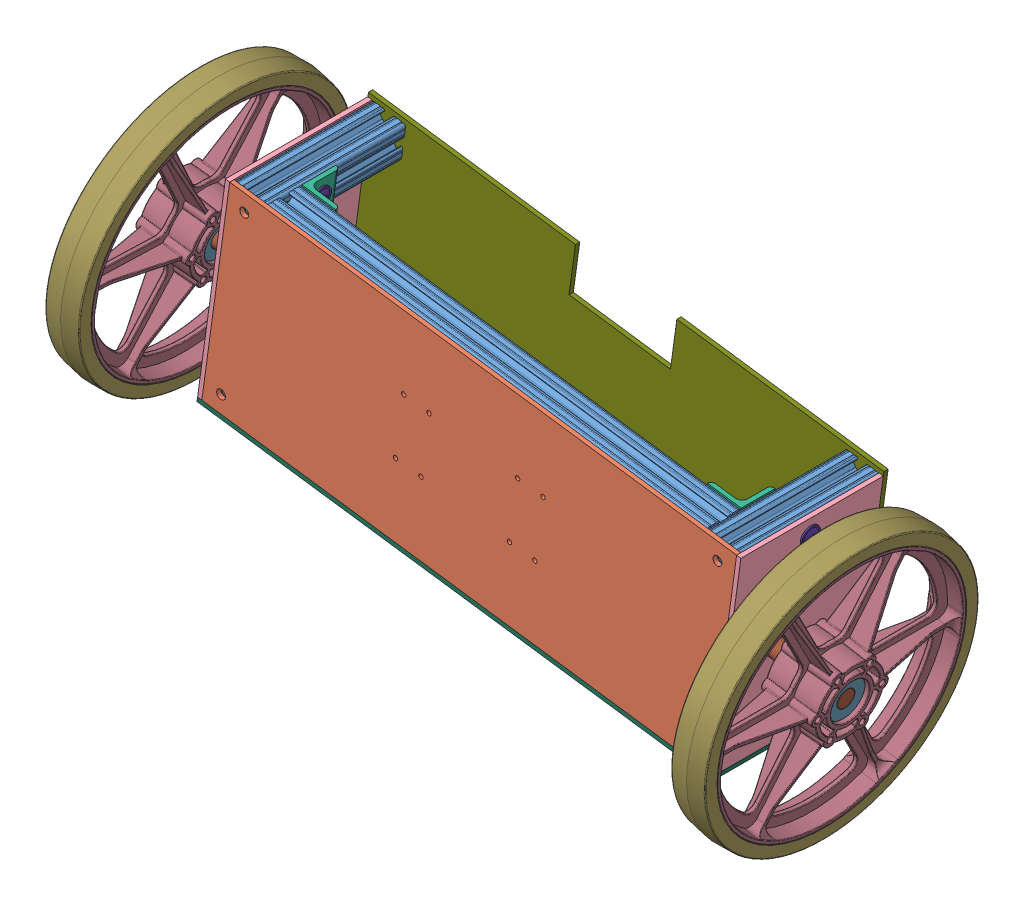
SolidWorks assembly MotorBox_Assy, configuration Default. Lengths in mm.
Overall size (541.44 344.28 279.2).
49 component instances, 18 part files, 75 mates.
Components (placement in the parent):
- 1010 PROFILE-3: 1010 PROFILE [13] at (161.8359 -35.0491 -15.875) x (-0.136082 -0.990698 0) z (0.990698 -0.136082 0) size (25.4 25.4 330.2)
- MotorBox_Base-1: MotorBox_Base [Default] at (-10.3695 -75.4912 -3.175) x (-0.990698 0.136082 0) z (0.136082 0.990698 0) size (381 3.17 152.4)
- Motor_Bracket-2: Motor_Bracket [Default] at (-159.2475 -55.0412 -31.75) x (0.136082 0.990698 0) z (-0.990698 0.136082 0) size (88.9 50.8 20.96)
- Motor_Bracket-3: Motor_Bracket [Default] at (138.5085 -95.9411 -31.75) x (-0.136082 -0.990698 0) z (0.990698 -0.136082 0) size (88.9 50.8 20.96)
- MotorBox_BackPlate-1: MotorBox_BackPlate [Default] at (0 0 -53.0225) x (0.990698 -0.136082 0) z (0.136082 0.990698 0) size (387.35 106.05 3.17) (hidden)
- 1010 PROFILE-5: 1010 PROFILE [4.05] at (-177.8743 11.6136 -3.175) x (0.990698 -0.136082 0) z (0 0 1) size (25.4 25.4 102.87)
- 1010 PROFILE-6: 1010 PROFILE [4.05] at (174.4178 -36.7773 -3.175) x (0.990698 -0.136082 0) z (0 0 1) size (25.4 25.4 102.87)
- motorbox_sidePlate-1: motorbox_sidePlate [Default] at (188.7279 -25.9237 0) x (0.990698 -0.136082 0) z (0.136082 0.990698 0) size (3.17 106.05 152.4)
- motorbox_sidePlate-3: motorbox_sidePlate [Default] at (-191.8733 26.3558 0) x (0.990698 -0.136082 0) z (0.136082 0.990698 0) size (3.17 106.05 152.4)
- MotorMount_3Dp2-1: MotorMount_3Dp2 [Default] at (17.0936 -79.2635 -3.175) x (-0.136082 -0.990698 0) z (0.990698 -0.136082 0) size (57.15 50.9 30.48)
- MotorMount_3Dp2-2: MotorMount_3Dp2 [Default] at (-37.8325 -71.7188 -3.175) x (0.136082 0.990698 0) z (-0.990698 0.136082 0) size (57.15 50.9 30.48)
- 90Deg 2Hole 4108-5: 90Deg 2Hole 4108 [Default] at (-190.2753 0.4978 -55.6714) x (0.990698 -0.136082 0) z (0.136082 0.990698 0) size (25.4 25.4 25.4)
- 90Deg 2Hole 4108-6: 90Deg 2Hole 4108 [Default] at (186.8188 -25.6615 -55.6714) x (-0.990698 0.136082 0) z (-0.136082 -0.990698 0) size (25.4 25.4 25.4)
- Motor_Coupler_WheelAssy-1: Motor_Coupler_WheelAssy [Default] at (82.653 -91.6609 -43.1023) x (0.117796 0.857568 -0.500701) z (-0.990698 0.136082 0) size (204.35 204.35 248.71)
  - Motor-1: Motor [Default] at (-2.7115 -11.3995 12.6743) size (45.1 45.1 159.4)
  - Coupler_Assembly-1: Coupler_Assembly [Default] at (-18.5282 -16.0979 -94.9854) x (0.697262 -0.716816 0) z (0 0 1) size (25.52 25.52 28.68)
    - CouplingCenter_59985K630-1: CouplingCenter_59985K630 [59985K63] at (7.6605 14.6137 19.5344) size (25.4 25.4 7.92)
    - halfInCoupling_59985K190-1: halfInCoupling_59985K190 [59985K19] at (7.6605 14.6137 19.4804) size (25.52 25.52 14.06)
    - 10mmCoupling_59985K305-1: 10mmCoupling_59985K305 [59985K305] at (7.6605 14.6137 19.5884) x (0 1 0) z (0 0 -1) size (25.52 25.52 14.06)
  - HalfInch_Shaft-1: HalfInch_Shaft [Default] at (-2.7115 -11.3995 -156.5786) size (12.7 12.7 76.2)
  - 8inWheel_AndyMarkAlternative-1: 8inWheel_AndyMarkAlternative [Default] at (-2.7115 -11.3995 -153.4798) size (204.35 204.35 38.11)
    - 2010 8 tread-1: 2010 8 tread [Default] at (0 0 12.7) size (204.35 204.35 25.4)
    - 2010 8 hub-1: 2010 8 hub [Default] at origin size (190.5 190.5 38.11)
    - r8 bearing-1: r8 bearing [Default] at (0 0 -3.0988) x (-0.726935 0.686706 0) z (0 0 1) size (28.57 28.57 6.35)
    - r8 bearing-2: r8 bearing [Default] at (0 0 28.575) x (0.399336 0.916804 0) z (0 0 -1) size (28.57 28.57 6.35)
- Motor_Coupler_WheelAssy-2: Motor_Coupler_WheelAssy [Default] at (-104.2482 -65.5549 -20.405) x (0.120301 0.875807 0.467429) z (0.990698 -0.136082 0) size (204.35 204.35 248.71)
  - Motor-1: Motor [Default] at (-2.7115 -11.3995 12.6743) size (45.1 45.1 159.4)
  - Coupler_Assembly-1: Coupler_Assembly [Default] at (-18.5282 -16.0979 -94.9854) x (0.697262 -0.716816 0) z (0 0 1) size (25.52 25.52 28.68)
    - CouplingCenter_59985K630-1: CouplingCenter_59985K630 [59985K63] at (7.6605 14.6137 19.5344) size (25.4 25.4 7.92)
    - halfInCoupling_59985K190-1: halfInCoupling_59985K190 [59985K19] at (7.6605 14.6137 19.4804) size (25.52 25.52 14.06)
    - 10mmCoupling_59985K305-1: 10mmCoupling_59985K305 [59985K305] at (7.6605 14.6137 19.5884) x (0 1 0) z (0 0 -1) size (25.52 25.52 14.06)
  - HalfInch_Shaft-1: HalfInch_Shaft [Default] at (-2.7115 -11.3995 -156.5786) size (12.7 12.7 76.2)
  - 8inWheel_AndyMarkAlternative-1: 8inWheel_AndyMarkAlternative [Default] at (-2.7115 -11.3995 -153.4798) size (204.35 204.35 38.11)
    - 2010 8 tread-1: 2010 8 tread [Default] at (0 0 12.7) size (204.35 204.35 25.4)
    - 2010 8 hub-1: 2010 8 hub [Default] at origin size (190.5 190.5 38.11)
    - r8 bearing-1: r8 bearing [Default] at (0 0 -3.0988) x (-0.726935 0.686706 0) z (0 0 1) size (28.57 28.57 6.35)
    - r8 bearing-2: r8 bearing [Default] at (0 0 28.575) x (0.399336 0.916804 0) z (0 0 -1) size (28.57 28.57 6.35)
- 1010 PROFILE-7: 1010 PROFILE [4.05] at (157.1353 -162.5959 -3.175) x (-0.136082 -0.990698 0) z (0 0 1) size (25.4 25.4 102.87)
- 1010 PROFILE-8: 1010 PROFILE [4.05] at (-195.1567 -114.205 -3.175) x (-0.136082 -0.990698 0) z (0 0 1) size (25.4 25.4 102.87)
- MotorBox_FrontPlate-1: MotorBox_FrontPlate [Default] at (-21.171 -154.1278 -53.0225) x (0.990698 -0.136082 0) z (0.136082 0.990698 0) size (387.35 106.05 3.17)
- MotorBox_TopPlate-1: MotorBox_TopPlate [Default] at (-10.3695 -75.4912 -109.22) x (-0.990698 0.136082 0) z (0 0 1) size (387.35 158.75 3.17)
- Tnut_47065T142-1: Tnut_47065T142 [47065T142] at (177.5632 -37.2094 -52.959) x (-0.136082 -0.990698 0) z (0 0 1) size (13.84 15.48 25.4)
- Tnut_47065T142-2: Tnut_47065T142 [47065T142] at (160.2808 -163.028 -52.959) x (-0.136082 -0.990698 0) z (0 0 1) size (13.84 15.48 25.4)
- Tnut_47065T142-3: Tnut_47065T142 [47065T142] at (-181.0197 12.0457 -52.959) x (0.136082 0.990698 0) z (0 0 1) size (13.84 15.48 25.4)
- Tnut_47065T142-4: Tnut_47065T142 [47065T142] at (-198.3022 -113.7729 -52.959) x (0.136082 0.990698 0) z (0 0 1) size (13.84 15.48 25.4)
- Tnut_47065T142-5: Tnut_47065T142 [47065T142] at (-152.7105 8.1571 -19.05) x (0.136082 0.990698 0) z (-0.990698 0.136082 0) size (13.84 15.48 25.4)
- Tnut_47065T142-6: Tnut_47065T142 [47065T142] at (-174.7288 11.1815 -41.275) x (-0.136082 -0.990698 0) z (0 0 1) size (13.84 15.48 25.4)
- Tnut_47065T142-7: Tnut_47065T142 [47065T142] at (171.2723 -36.3453 -41.275) x (-0.135988 -0.990011 0.037224) z (-0.005066 -0.036878 -0.999307) size (13.84 15.48 25.4)
- Tnut_47065T142-8: Tnut_47065T142 [47065T142] at (149.2541 -33.3208 -19.05) x (0.136082 0.990698 0) z (-0.990698 0.136082 0) size (13.84 15.48 25.4)
Mates (geometry in assembly coordinates):
- Coincident34: coincident anti-aligned: plane of MotorBox_Base-1 through (-10.3695 -75.4912 -3.175) normal (0 0 -1); plane of Motor_Bracket-2 through (-150.0531 -11.4368 -3.175) normal (0 0 1)
- Coincident39: coincident anti-aligned: plane of MotorBox_Base-1 through (-10.3695 -75.4912 -3.175) normal (0 0 -1); plane of Motor_Bracket-3 through (129.3142 -139.5455 -3.175) normal (0 0 1)
- Coincident44: coincident aligned: plane of MotorBox_Base-1 through (-10.3695 -75.4912 0) normal (0 0 1); plane of MotorBox_BackPlate-1 through (-191.4413 29.5012 0) normal (0 0 1)
- Distance23: distance = 3.175 mm aligned: plane of MotorBox_Base-1 through (-209.4668 -125.0586 0) normal (-0.990698 0.136082 0); plane of MotorBox_BackPlate-1 through (-191.4413 29.5012 -106.045) normal (-0.990698 0.136082 0)
- Coincident46: coincident anti-aligned: plane of MotorBox_Base-1 through (188.7279 -25.9237 0) normal (0.136082 0.990698 0); plane of MotorBox_BackPlate-1 through (0 0 -53.0225) normal (-0.136082 -0.990698 0)
- Distance18: distance = 12.7 mm anti-aligned: plane of 1010 PROFILE-3; plane of 1010 PROFILE-5 through (-177.8743 11.6136 -3.175) normal (0 0 1)
- Coincident49: coincident anti-aligned: plane of 1010 PROFILE-3; plane of 1010 PROFILE-5
- Distance19: distance = 15.875 mm anti-aligned: plane of 1010 PROFILE-5; plane of MotorBox_BackPlate-1 through (-191.4413 29.5012 -106.045) normal (-0.990698 0.136082 0)
- Distance20: distance = 12.7 mm anti-aligned: plane of 1010 PROFILE-3; plane of 1010 PROFILE-6 through (174.4178 -36.7773 -3.175) normal (0 0 1)
- Coincident52: coincident anti-aligned: plane of 1010 PROFILE-3; plane of 1010 PROFILE-6
- Distance22: distance = 355.6 mm aligned: plane of 1010 PROFILE-6; plane of 1010 PROFILE-5
- Coincident55: coincident anti-aligned: plane of MotorBox_Base-1 through (167.9889 -176.906 0) normal (0.990698 -0.136082 0); plane of motorbox_sidePlate-1 through (188.7279 -25.9237 0) normal (-0.990698 0.136082 0)
- Coincident56: coincident anti-aligned: plane of MotorBox_BackPlate-1 through (0 0 -53.0225) normal (-0.136082 -0.990698 0); plane of motorbox_sidePlate-1 through (191.8733 -26.3558 0) normal (0.136082 0.990698 0)
- Coincident57: coincident aligned: plane of MotorBox_Base-1 through (-10.3695 -75.4912 0) normal (0 0 1); plane of motorbox_sidePlate-1 through (191.8733 -26.3558 0) normal (0 0 1)
- Coincident61: coincident anti-aligned: plane of MotorBox_BackPlate-1 through (0 0 -53.0225) normal (-0.136082 -0.990698 0); plane of motorbox_sidePlate-3 through (-188.7279 25.9237 0) normal (0.136082 0.990698 0)
- Coincident62: coincident aligned: plane of MotorBox_Base-1 through (-10.3695 -75.4912 0) normal (0 0 1); plane of motorbox_sidePlate-3 through (-188.7279 25.9237 0) normal (0 0 1)
- Coincident63: coincident anti-aligned: plane of MotorBox_Base-1 through (-209.4668 -125.0586 0) normal (-0.990698 0.136082 0); plane of motorbox_sidePlate-3 through (-188.7279 25.9237 0) normal (0.990698 -0.136082 0)
- Coincident65: coincident anti-aligned: plane of MotorBox_Base-1 through (-10.3695 -75.4912 -3.175) normal (0 0 -1); plane of 1010 PROFILE-6 through (171.6806 -44.1442 -3.175) normal (0 0 1)
- Coincident66: coincident anti-aligned: plane of 1010 PROFILE-3 through (-163.5642 22.4672 -9.5419) normal (0.136082 0.990698 0); plane of MotorBox_BackPlate-1 through (0 0 -53.0225) normal (-0.136082 -0.990698 0)
- Coincident70: coincident anti-aligned: plane of 1010 PROFILE-5 through (-166.592 0.4238 -106.045) normal (0.990698 -0.136082 0); plane of 90Deg 2Hole 4108-5 through (-163.5642 22.4672 -53.975) normal (-0.990698 0.136082 0)
- Coincident71: coincident: plane of 1010 PROFILE-3 through (-164.4306 16.1595 -28.575) normal (0 0 -1); line of 90Deg 2Hole 4108-5 through (-138.4004 19.0107 -28.575) axis (-0.136082 -0.990698 0)
- Coincident72: coincident: plane of MotorBox_BackPlate-1 through (0 0 -53.0225) normal (-0.136082 -0.990698 0); line of 90Deg 2Hole 4108-5 through (-141.5459 19.4428 -31.75) axis (-0.990698 0.136082 0)
- Coincident73: coincident anti-aligned: plane of 1010 PROFILE-6 through (163.1356 -25.5875 -106.045) normal (-0.990698 0.136082 0); plane of 90Deg 2Hole 4108-6 through (160.1077 -47.6309 -53.975) normal (0.990698 -0.136082 0)
- Coincident74: coincident anti-aligned: plane of 1010 PROFILE-3 through (-166.592 0.4238 -28.575) normal (0 0 -1); plane of 90Deg 2Hole 4108-6 through (160.1077 -47.6309 -28.575) normal (0 0 1)
- Coincident75: coincident anti-aligned: plane of MotorBox_BackPlate-1 through (0 0 -53.0225) normal (-0.136082 -0.990698 0); plane of 90Deg 2Hole 4108-6 through (163.5642 -22.4672 -50.8) normal (0.136082 0.990698 0)
- Coincident92: coincident anti-aligned: plane of MotorBox_Base-1 through (-10.3695 -75.4912 -3.175) normal (0 0 -1); plane of MotorMount_3Dp2-1 through (51.1786 -55.1021 -3.175) normal (0 0 1)
- Coincident93: coincident anti-aligned: plane of MotorBox_Base-1 through (-10.3695 -75.4912 -3.175) normal (0 0 -1); plane of MotorMount_3Dp2-2 through (-71.9176 -95.8802 -3.175) normal (0 0 1)
- Concentric4: concentric anti-aligned: cylinder of MotorMount_3Dp2-1 through (47.29 -83.4113 -31.877) axis (-0.990698 0.136082 0) radius 19.1089; cylinder of Motor_Coupler_WheelAssy-1/Motor-1 through (-4.9373 -76.2373 -31.877) axis (0.990698 -0.136082 0) radius 18.415
- Distance27: distance = 25.4 mm anti-aligned: plane of 1010 PROFILE-3 through (162.0685 -33.3557 -8.2042) normal (0.990698 -0.136082 0); plane of motorbox_sidePlate-1 through (188.7279 -25.9237 0) normal (-0.990698 0.136082 0)
- Coincident98: coincident: plane of 1010 PROFILE-3 through (-163.5642 22.4672 -9.5419) normal (0.136082 0.990698 0); point of assembly
- Distance29: distance = 76.2 mm: line of motorbox_sidePlate-1 through (188.7279 -25.9237 -106.045) axis (0 0 1); plane of Motor_Bracket-3
- Parallel3: parallel anti-aligned: plane of Motor_Bracket-3 through (138.5085 -95.9411 -71.12) normal (0.990698 -0.136082 0); plane of motorbox_sidePlate-1 through (188.7279 -25.9237 0) normal (-0.990698 0.136082 0)
- Parallel4: parallel anti-aligned: plane of Motor_Bracket-2 through (-159.2475 -55.0412 -71.12) normal (-0.990698 0.136082 0); plane of motorbox_sidePlate-3 through (-188.7279 25.9237 0) normal (0.990698 -0.136082 0)
- Distance30: distance = 76.2 mm aligned: plane of motorbox_sidePlate-3 through (-188.7279 25.9237 0) normal (0.136082 0.990698 0); plane of Motor_Bracket-2
- Coincident102: coincident aligned: plane of MotorBox_Base-1 through (-10.3695 -75.4912 0) normal (0 0 1); plane of assembly through (0 0 0) normal (0 0 1)
- Distance31: distance = 76.2 mm aligned: plane of motorbox_sidePlate-3 through (-188.7279 25.9237 0) normal (0.136082 0.990698 0); plane of MotorMount_3Dp2-2
- Distance32: distance = 76.2 mm anti-aligned: plane of MotorMount_3Dp2-1; plane of motorbox_sidePlate-1 through (191.8733 -26.3558 0) normal (0.136082 0.990698 0)
- Coincident105: coincident anti-aligned: plane of Motor_Bracket-3 through (135.363 -95.509 -71.12) normal (-0.990698 0.136082 0); plane of Motor_Coupler_WheelAssy-1/Motor-1 through (135.363 -95.509 -31.877) normal (0.990698 -0.136082 0)
- Distance33: distance = 88.9 mm anti-aligned: plane of Motor_Bracket-3 through (135.363 -95.509 -71.12) normal (-0.990698 0.136082 0); plane of MotorMount_3Dp2-1 through (47.29 -83.4113 -31.877) normal (0.990698 -0.136082 0)
- Concentric9: concentric aligned: circle of Motor_Bracket-2; circle of Motor_Coupler_WheelAssy-2/Motor-1
- Coincident107: coincident anti-aligned: plane of Motor_Bracket-2 through (-156.102 -55.4733 -71.12) normal (0.990698 -0.136082 0); plane of Motor_Coupler_WheelAssy-2/Motor-1 through (-156.102 -55.4733 -31.75) normal (-0.990698 0.136082 0)
- Distance34: distance = 88.9 mm anti-aligned: plane of Motor_Bracket-2 through (-156.102 -55.4733 -71.12) normal (0.990698 -0.136082 0); plane of MotorMount_3Dp2-2 through (-68.029 -67.571 -31.877) normal (-0.990698 0.136082 0)
- Distance35: distance = 6.35 mm anti-aligned: plane of Motor_Coupler_WheelAssy-2/Coupler_Assembly-1/halfInCoupling_59985K190-1 through (-192.8064 -50.4316 -31.75) normal (-0.990698 0.136082 0); plane of motorbox_sidePlate-3 through (-188.7279 25.9237 0) normal (0.990698 -0.136082 0)
- Distance36: distance = 6.35 mm anti-aligned: plane of motorbox_sidePlate-1 through (188.7279 -25.9237 0) normal (-0.990698 0.136082 0); plane of Motor_Coupler_WheelAssy-1/Coupler_Assembly-1/halfInCoupling_59985K190-1 through (172.0675 -100.5507 -31.877) normal (0.990698 -0.136082 0)
- Angle1: planar angle = 0.524408 rad anti-aligned: plane of Motor_Coupler_WheelAssy-1/8inWheel_AndyMarkAlternative-1/2010 8 hub-1; plane of assembly through (0 0 0) normal (0 0 1)
- Coincident108: coincident anti-aligned: plane of MotorBox_Base-1 through (-10.3695 -75.4912 -3.175) normal (0 0 -1); plane of 1010 PROFILE-7 through (149.7685 -159.8587 -3.175) normal (0 0 1)
- Coincident58: coincident anti-aligned: plane of motorbox_sidePlate-1 through (188.7279 -25.9237 0) normal (-0.990698 0.136082 0); plane of 1010 PROFILE-7 through (168.4175 -173.7857 -106.045) normal (0.990698 -0.136082 0)
- Coincident59: coincident aligned: plane of motorbox_sidePlate-1 through (171.1344 -177.3381 0) normal (-0.136082 -0.990698 0); plane of 1010 PROFILE-7 through (161.6813 -176.0396 -106.045) normal (-0.136082 -0.990698 0)
- Coincident60: coincident anti-aligned: plane of MotorBox_Base-1 through (-10.3695 -75.4912 -3.175) normal (0 0 -1); plane of 1010 PROFILE-8 through (-202.5236 -111.4678 -3.175) normal (0 0 1)
- Coincident109: coincident anti-aligned: plane of motorbox_sidePlate-3 through (-188.7279 25.9237 0) normal (0.990698 -0.136082 0); plane of 1010 PROFILE-8 through (-208.6004 -118.7509 -106.045) normal (-0.990698 0.136082 0)
- Coincident110: coincident aligned: plane of motorbox_sidePlate-3 through (-209.4668 -125.0586 0) normal (-0.136082 -0.990698 0); plane of 1010 PROFILE-8 through (-206.3465 -125.4872 -106.045) normal (-0.136082 -0.990698 0)
- Coincident67: coincident aligned: line of motorbox_sidePlate-1 through (171.1344 -177.3381 0) axis (0 0 -1); line of MotorBox_FrontPlate-1 through (171.1344 -177.3381 0) axis (0 0 -1)
- Coincident68: coincident: line of MotorBox_Base-1 through (-209.4668 -125.0586 0) axis (0.990698 -0.136082 0); plane of MotorBox_FrontPlate-1 through (-212.6123 -124.6265 0) normal (0 0 1)
- Coincident69: coincident anti-aligned: line of motorbox_sidePlate-3 through (-212.6123 -124.6265 0) axis (0 0 -1); line of MotorBox_FrontPlate-1 through (-212.6123 -124.6265 -106.045) axis (0 0 1)
- Coincident111: coincident anti-aligned: line of motorbox_sidePlate-3 through (-212.6123 -124.6265 -106.045) axis (0.136082 0.990698 0); line of MotorBox_TopPlate-1 through (-191.4413 29.5012 -106.045) axis (-0.136082 -0.990698 0)
- Coincident112: coincident aligned: line of motorbox_sidePlate-1 through (171.1344 -177.3381 -106.045) axis (0.136082 0.990698 0); line of MotorBox_TopPlate-1 through (170.7023 -180.4835 -106.045) axis (0.136082 0.990698 0)
- Coincident113: coincident aligned: plane of MotorBox_BackPlate-1 through (0.4321 3.1455 -53.0225) normal (0.136082 0.990698 0); plane of MotorBox_TopPlate-1 through (192.3054 -23.2103 -106.045) normal (0.136082 0.990698 0)
- Concentric10: concentric anti-aligned: circle of motorbox_sidePlate-1; circle of Tnut_47065T142-1
- Coincident114: coincident anti-aligned: plane of motorbox_sidePlate-1 through (191.8733 -26.3558 0) normal (0.990698 -0.136082 0); plane of Tnut_47065T142-1 through (190.1451 -38.9376 -52.959) normal (-0.990698 0.136082 0)
- Concentric11: concentric anti-aligned: circle of motorbox_sidePlate-1; circle of Tnut_47065T142-2
- Coincident115: coincident anti-aligned: plane of motorbox_sidePlate-1 through (191.8733 -26.3558 0) normal (0.990698 -0.136082 0); circle of Tnut_47065T142-2
- Concentric12: concentric aligned: circle of motorbox_sidePlate-3; circle of Tnut_47065T142-3
- Coincident116: coincident anti-aligned: plane of motorbox_sidePlate-3 through (-191.8733 26.3558 0) normal (-0.990698 0.136082 0); circle of Tnut_47065T142-3
- Concentric13: concentric aligned: circle of motorbox_sidePlate-3; circle of Tnut_47065T142-4
- Coincident117: coincident anti-aligned: plane of motorbox_sidePlate-3 through (-191.8733 26.3558 0) normal (-0.990698 0.136082 0); circle of Tnut_47065T142-4
- Concentric14: concentric aligned: circle of 90Deg 2Hole 4108-5; circle of Tnut_47065T142-5
- Parallel5: parallel: line of 1010 PROFILE-3 through (-164.4306 16.1595 -28.575) axis (0.990698 -0.136082 0); plane of Tnut_47065T142-5 through (-159.0317 14.6338 -20.4978) normal (0.136082 0.990698 0)
- Coincident119: coincident anti-aligned: plane of 90Deg 2Hole 4108-5 through (-141.5459 19.4428 -31.75) normal (0 0 -1); plane of Tnut_47065T142-5 through (-152.7105 8.1571 -31.75) normal (0 0 1)
- Concentric15: concentric aligned: circle of 90Deg 2Hole 4108-5; circle of Tnut_47065T142-6
- Coincident120: coincident anti-aligned: plane of 90Deg 2Hole 4108-5 through (-160.4187 22.0352 -36.5252) normal (0.990698 -0.136082 0); plane of Tnut_47065T142-6 through (-162.1469 9.4533 -41.275) normal (-0.990698 0.136082 0)
- Concentric16: concentric aligned: circle of 90Deg 2Hole 4108-6; circle of Tnut_47065T142-7
- Coincident121: coincident anti-aligned: plane of 90Deg 2Hole 4108-6 through (156.9622 -47.1989 -36.5252) normal (-0.990698 0.136082 0); circle of Tnut_47065T142-7
- Concentric17: concentric aligned: circle of 90Deg 2Hole 4108-6; circle of Tnut_47065T142-8
- Coincident122: coincident anti-aligned: plane of 90Deg 2Hole 4108-6 through (138.0894 -44.6065 -31.75) normal (0 0 -1); circle of Tnut_47065T142-8
- Parallel6: parallel: line of 1010 PROFILE-3 through (-166.7303 -0.5827 -28.5748) axis (0.990698 -0.136082 0); plane of Tnut_47065T142-8 through (141.4206 -37.8533 -20.4978) normal (-0.136082 -0.990698 0)
